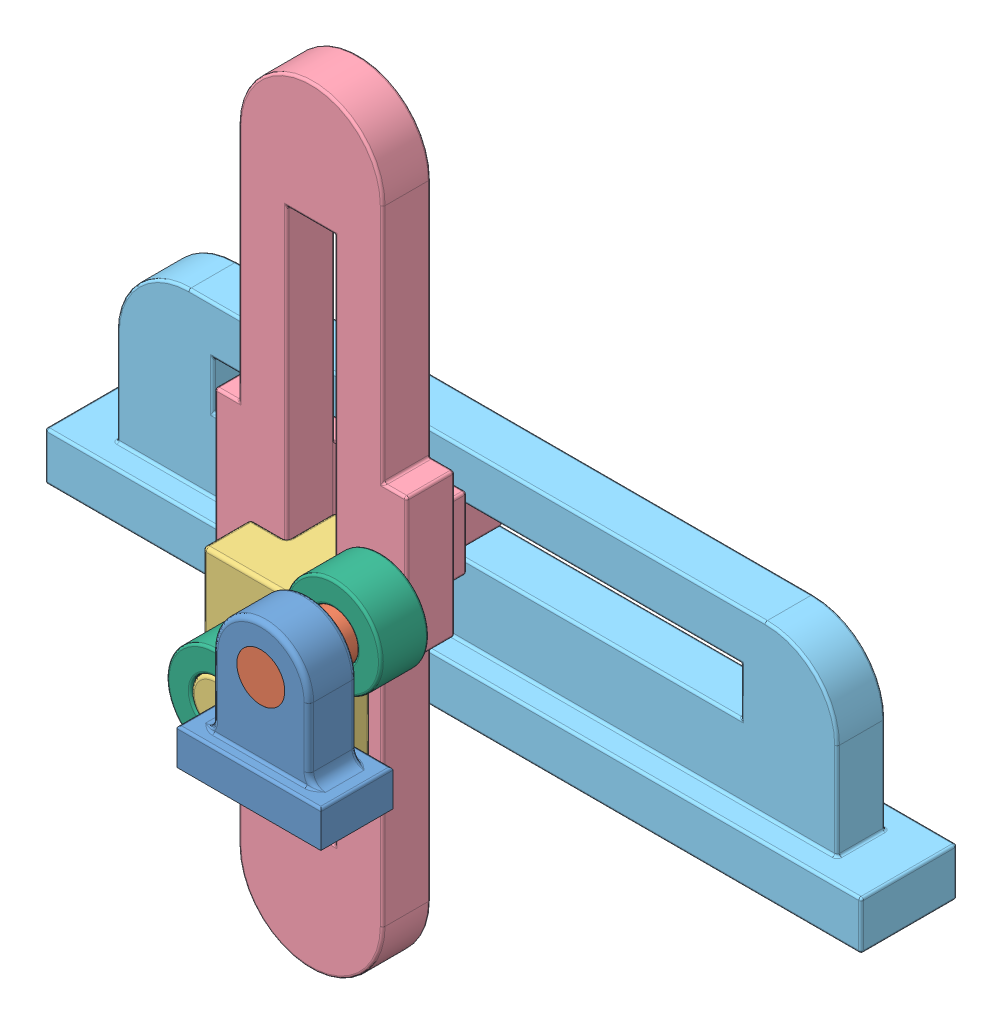
SolidWorks assembly L12 Mecanism, configuration Default. Lengths in mm.
Overall size (340 320 135).
6 component instances, 6 part files, 19 mates.
Components (placement in the parent):
- L12 Part1-1: L12 Part1 [Default] at (-6.8949 63.329 63.1731) x (1 0 0) z (0 -1 0) size (60 30 65)
- L12 Part5-1: L12 Part5 [Default] at (-6.8949 93.329 23.1731) size (20 20 50)
- L12 Part3-1: L12 Part3 [Default] at (-31.1274 43.568 23.1731) x (-1 0 0) z (0 -1 0) size (50 60 70)
- L12 Part4-1: L12 Part4 [Default] at (-56.1274 218.3386 3.1731) x (-1 0 0) z (0 0 -1) size (80 320 50)
- L12 Part6-1: L12 Part6 [Default] at (-126.8569 98.3386 -46.8269) size (340 90 40)
- L12 Part2-2: L12 Part2 [Default] at (-56.1274 43.568 33.1731) x (-0.710872 0.703322 0) z (0 0 1) size (40 110 20)
Mates (geometry in assembly coordinates):
- Concentric1: concentric aligned: cylinder of L12 Part1-1 through (-6.8949 93.329 73.1731) axis (0 0 -1) radius 10; cylinder of L12 Part5-1 through (-6.8949 93.329 73.1731) axis (0 0 -1) radius 10
- Coincident1: coincident aligned: plane of L12 Part1-1 through (-6.8949 93.329 73.1731) normal (0 0 1); plane of L12 Part5-1 through (-6.8949 93.329 73.1731) normal (0 0 1)
- Concentric2: concentric aligned: cylinder of L12 Part5-1 through (-6.8949 93.329 73.1731) axis (0 0 -1) radius 10; cylinder of L12 Part2-1 through (2.2637 66.3635 27.9527) axis (0 0 -1) radius 10
- Coincident2: coincident aligned: plane of L12 Part5-1 through (-6.8949 93.329 23.1731) normal (0 0 -1); plane of L12 Part2-1 through (-7.7363 135.6455 7.9527) normal (0 0 -1)
- Concentric3: concentric aligned: cylinder of L12 Part2-1 through (-7.7363 135.6455 27.9527) axis (0 0 -1) radius 10; cylinder of L12 Part3-1 through (-37.5751 30.4107 43.1731) axis (0 0 -1) radius 10
- Coincident3: coincident aligned: plane of L12 Part2-1 through (-7.7363 135.6455 27.9527) normal (0 0 1); plane of L12 Part3-1 through (-37.5751 30.4107 43.1731) normal (0 0 1)
- Coincident4: coincident anti-aligned: plane of L12 Part3-1 through (-1.7842 128.1581 3.1731) normal (1 0 0); plane of L12 Part4-1 through (-1.7842 -21.6614 -16.8269) normal (-1 0 0)
- Parallel4: parallel aligned: plane of L12 Part1-1 through (13.1051 93.329 73.1731) normal (1 0 0); plane of L12 Part4-1 through (18.2158 -41.6614 -16.8269) normal (1 0 0)
- Coincident7: coincident aligned: plane of L12 Part3-1 through (-1.7842 128.1581 -16.8269) normal (0 0 -1); plane of L12 Part4-1 through (-11.7842 218.3386 -16.8269) normal (0 0 -1)
- LimitDistance1: limit distance = 119.7706 mm anti-aligned: plane of L12 Part3-1 through (-31.1274 78.568 23.1731) normal (0 1 0); plane of L12 Part4-1 through (-46.1274 198.3386 -16.8269) normal (0 -1 0)
- LimitDistance2: limit distance = 30.2294 mm anti-aligned: plane of L12 Part3-1 through (-31.1274 8.568 23.1731) normal (0 -1 0); plane of L12 Part4-1 through (-46.1274 -21.6614 -16.8269) normal (0 1 0)
- Coincident8: coincident anti-aligned: plane of L12 Part4-1 through (18.2158 98.3386 -46.8269) normal (0 1 0); plane of L12 Part6-1 through (-126.8569 98.3386 -26.8269) normal (0 -1 0)
- Coincident9: coincident aligned: plane of L12 Part4-1 through (-11.7842 218.3386 -46.8269) normal (0 0 -1); plane of L12 Part6-1 through (103.1431 88.3386 -46.8269) normal (0 0 -1)
- LimitDistance3: limit distance = 40.7295 mm anti-aligned: plane of L12 Part6-1 through (-126.8569 98.3386 -26.8269) normal (1 0 0); plane of L12 Part4-1 through (-86.1274 98.3386 -46.8269) normal (-1 0 0)
- LimitDistance4: limit distance = 119.2705 mm anti-aligned: plane of L12 Part6-1 through (93.1431 98.3386 -26.8269) normal (-1 0 0); plane of L12 Part4-1 through (-26.1274 98.3386 -46.8269) normal (1 0 0)
- Concentric8: concentric aligned: cylinder of L12 Part5-1 through (-6.8949 93.329 73.1731) axis (0 0 -1) radius 10; cylinder of L12 Part2-2 through (-6.8949 93.329 43.1731) axis (0 0 -1) radius 10
- Coincident18: coincident aligned: plane of L12 Part5-1 through (-6.8949 93.329 23.1731) normal (0 0 -1); plane of L12 Part2-2 through (-11.7842 163.1581 23.1731) normal (0 0 -1)
- Concentric9: concentric aligned: cylinder of L12 Part3-1 through (-11.7842 163.1581 43.1731) axis (0 0 -1) radius 10; cylinder of L12 Part2-2 through (-11.7842 163.1581 43.1731) axis (0 0 -1) radius 10
- Coincident19: coincident anti-aligned: plane of L12 Part3-1 through (-36.7842 128.1581 23.1731) normal (0 0 1); plane of L12 Part2-2 through (-11.7842 163.1581 23.1731) normal (0 0 -1)
